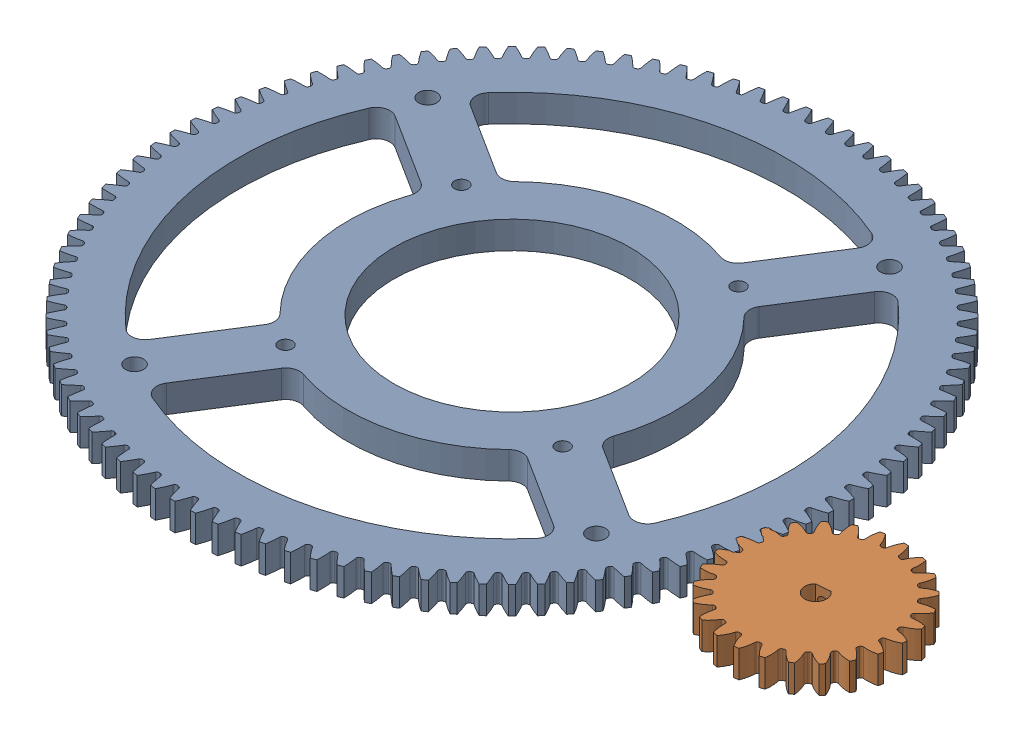
SolidWorks assembly 2. Gears, configuration Default. Lengths in mm.
Overall size (218.41 12.67 211.11).
2 component instances, 2 part files, 5 mates.
Components (placement in the parent):
- 2. Gear Base-1: 2. Gear Base [2664N505] at (-39.5276 0 -20.4612) x (0.84431 0 0.535855) z (0 1 0) size (152.96 152.96 6.35)
- 2. Gear Driver-1: 2. Gear Driver [2664N513] at (51.4417 0 0) x (-0.085113 0 -0.996371) z (0 1 0) size (40.4 40.47 6.35)
Mates (geometry in assembly coordinates):
- Coincident1: coincident aligned: plane of 2. Gear Base-1 through (-39.5276 0 -20.4612) normal (0 1 0); plane of 2. Gear Driver-1 through (51.4417 0 0) normal (0 1 0)
- Distance2: distance: point of 2. Gear Base-1; point of 2. Gear Driver-1
- GearMate2: gear = 150 : 37.5 mm: circle of 2. Gear Driver-1; circle of 2. Gear Base-1
- Coincident9: coincident aligned: plane of 2. Gear Base-1 through (-39.5276 0 -20.4612) normal (0 1 0)
- Coincident10: coincident: line of 2. Gear Driver-1 through (51.4417 0 0) axis (0 -1 0)
